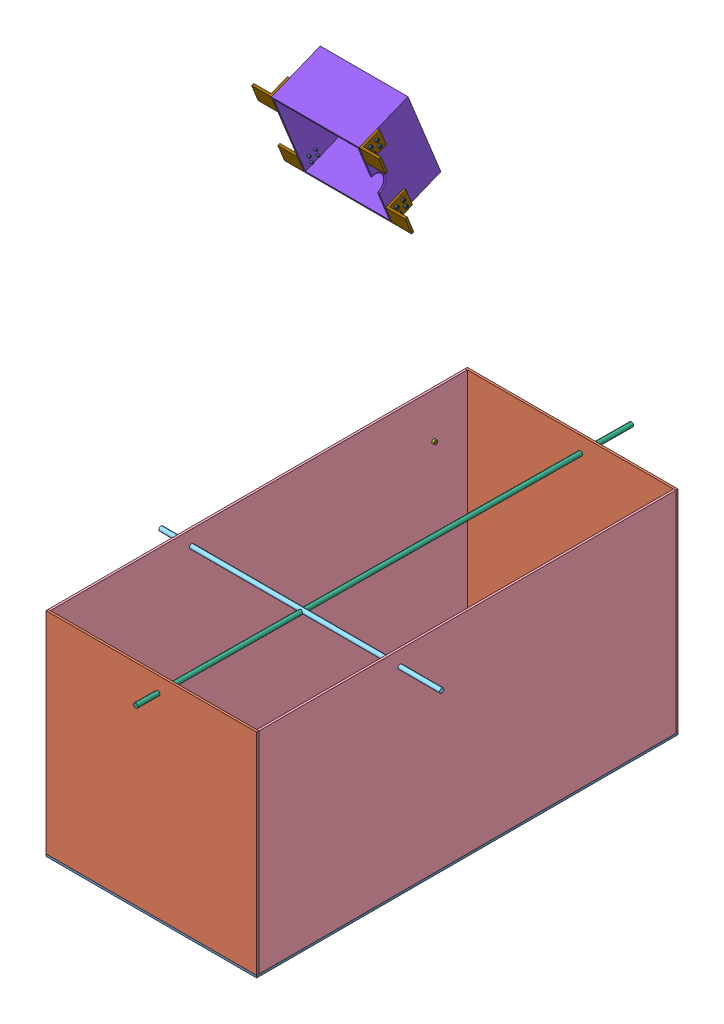
SolidWorks assembly Full Assem 10-31-19, configuration Default. Lengths in mm.
Overall size (741.82 468.9 824.09).
30 component instances, 10 part files, 50 mates.
Components (placement in the parent):
- Base of basin-1: Base of basin [Default] at (176.4368 339.4284 479.3371) size (304.8 3.17 609.6)
- Ends of basin-1: Ends of basin [Default] at (176.4368 495.0034 780.9621) x (0 0 1) z (-1 0 0) size (3.17 304.8 304.8)
- Metalsheet-1: Metalsheet [Default] at (176.9569 345.7784 489.4107) size (254 3.17 254)
- Right Side of basin-1: Right Side of basin [Default] at (24.0368 495.0034 476.1621) size (3.17 304.8 603.25)
- Ends of basin-3: Ends of basin [Default] at (176.4368 495.0034 174.5371) x (0 0 1) z (-1 0 0) size (3.17 304.8 304.8)
- Right Side of basin-2: Right Side of basin [Default] at (325.6618 495.0034 476.1621) size (3.17 304.8 603.25)
- Metal rod 1ft-1: Metal rod 1ft [Default] at (-17.2943 625.8145 576.4898) size (406.4 6.35 6.35)
- Metal rod 2ft-1: Metal rod 2ft [Default] at (191.5519 624.8435 104.5487) x (-0.008727 0 0.999962) z (-0.999962 0 -0.008727) size (711.2 6.35 6.35)
- Standard Servo S3003-1: Standard Servo S3003 [Default] at (12.8608 571.9051 226.3122) x (0 -0.999962 -0.008727) z (1 0 0) size (55.2 19.69 44.46)
- Gear Box-1: Gear Box [Default] at (-260.6438 720.9097 86.1005) x (0 0.927178 0.374622) z (0 0.374622 -0.927178) size (127 127 76.2)
- Gear box Braket-2: Gear box Braket [Default] at (-197.1438 679.1614 53.8226) x (0 -0.927178 -0.374622) z (1 0 0) size (25.4 28.57 28.57)
- Gear box Braket-3: Gear box Braket [Default] at (-324.1438 679.1614 53.8226) x (0 0.927178 0.374622) z (-1 0 0) size (25.4 28.57 28.57)
- Gear box Braket-4: Gear box Braket [Default] at (-197.1438 773.3627 91.8842) x (0 -0.927178 -0.374622) z (1 0 0) size (25.4 28.57 28.57)
- Gear box Braket-5: Gear box Braket [Default] at (-324.1438 773.3627 91.8842) x (0 0.927178 0.374622) z (-1 0 0) size (25.4 28.57 28.57)
- socket head cap screw_ai-2: socket head cap screw_ai [HX-SHCS 0.112-40x0.375x0.375-N] at (-330.1636 776.5265 97.6142) size (12.37 4.65 4.65)
- socket head cap screw_ai-3: socket head cap screw_ai [HX-SHCS 0.112-40x0.375x0.375-N] at (-330.1636 767.1064 93.808) size (12.37 4.65 4.65)
- socket head cap screw_ai-4: socket head cap screw_ai [HX-SHCS 0.112-40x0.375x0.375-N] at (-330.1636 770.9125 84.3879) size (12.37 4.65 4.65)
- socket head cap screw_ai-5: socket head cap screw_ai [HX-SHCS 0.112-40x0.375x0.375-N] at (-330.1636 780.3327 88.1941) size (12.37 4.65 4.65)
- socket head cap screw_ai-6: socket head cap screw_ai [HX-SHCS 0.112-40x0.375x0.375-N] at (-330.1636 676.7113 46.3263) size (12.37 4.65 4.65)
- socket head cap screw_ai-7: socket head cap screw_ai [HX-SHCS 0.112-40x0.375x0.375-N] at (-330.1636 686.1314 50.1325) size (12.37 4.65 4.65)
- socket head cap screw_ai-8: socket head cap screw_ai [HX-SHCS 0.112-40x0.375x0.375-N] at (-330.1636 682.3252 59.5526) size (12.37 4.65 4.65)
- socket head cap screw_ai-9: socket head cap screw_ai [HX-SHCS 0.112-40x0.375x0.375-N] at (-330.1636 672.9051 55.7465) size (12.37 4.65 4.65)
- socket head cap screw_ai-10: socket head cap screw_ai [HX-SHCS 0.112-40x0.375x0.375-N] at (-191.124 780.3327 88.1941) x (-1 0 0) z (0 0.924225 0.381849) size (12.37 4.65 4.65)
- socket head cap screw_ai-11: socket head cap screw_ai [HX-SHCS 0.112-40x0.375x0.375-N] at (-191.124 770.9125 84.3879) x (-1 0 0) z (0 0.924225 0.381849) size (12.37 4.65 4.65)
- socket head cap screw_ai-12: socket head cap screw_ai [HX-SHCS 0.112-40x0.375x0.375-N] at (-191.124 776.5265 97.6142) x (-1 0 0) z (0 0.924225 0.381849) size (12.37 4.65 4.65)
- socket head cap screw_ai-13: socket head cap screw_ai [HX-SHCS 0.112-40x0.375x0.375-N] at (-191.124 767.1064 93.808) x (-1 0 0) z (0 0.924225 0.381849) size (12.37 4.65 4.65)
- socket head cap screw_ai-14: socket head cap screw_ai [HX-SHCS 0.112-40x0.375x0.375-N] at (-191.124 682.3252 59.5526) x (-1 0 0) z (0 0.924225 0.381849) size (12.37 4.65 4.65)
- socket head cap screw_ai-15: socket head cap screw_ai [HX-SHCS 0.112-40x0.375x0.375-N] at (-191.124 686.1314 50.1325) x (-1 0 0) z (0 0.924225 0.381849) size (12.37 4.65 4.65)
- socket head cap screw_ai-16: socket head cap screw_ai [HX-SHCS 0.112-40x0.375x0.375-N] at (-191.124 676.7113 46.3263) x (-1 0 0) z (0 0.924225 0.381849) size (12.37 4.65 4.65)
- socket head cap screw_ai-17: socket head cap screw_ai [HX-SHCS 0.112-40x0.375x0.375-N] at (-191.124 672.9051 55.7465) x (-1 0 0) z (0 0.924225 0.381849) size (12.37 4.65 4.65)
Mates (geometry in assembly coordinates):
- Coincident2: coincident aligned: line of Base of basin-1 through (24.0368 342.6034 784.1371) axis (1 0 0); line of Ends of basin-1 through (24.0368 342.6034 784.1371) axis (1 0 0)
- Coincident3: coincident anti-aligned: line of Base of basin-1 through (24.0368 342.6034 174.5371) axis (0 0 1); line of Ends of basin-1 through (24.0368 342.6034 784.1371) axis (0 0 -1)
- Coincident4: coincident aligned: line of Base of basin-1 through (24.0368 342.6034 174.5371) axis (0 0 1); line of Right Side of basin-1 through (24.0368 342.6034 177.7121) axis (0 0 1)
- Coincident5: coincident anti-aligned: line of Ends of basin-1 through (24.0368 647.4034 780.9621) axis (0 -1 0); line of Right Side of basin-1 through (24.0368 342.6034 780.9621) axis (0 1 0)
- Coincident8: coincident aligned: line of Ends of basin-1 through (328.8368 342.6034 780.9621) axis (0 1 0); line of Right Side of basin-2 through (328.8368 342.6034 780.9621) axis (0 1 0)
- Coincident9: coincident anti-aligned: line of Base of basin-1 through (328.8368 342.6034 784.1371) axis (0 0 -1); line of Right Side of basin-2 through (328.8368 342.6034 177.7121) axis (0 0 1)
- Coincident12: coincident anti-aligned: line of Right Side of basin-1 through (24.0368 342.6034 177.7121) axis (0 1 0); line of Ends of basin-3 through (24.0368 647.4034 177.7121) axis (0 -1 0)
- Coincident13: coincident anti-aligned: line of Base of basin-1 through (24.0368 342.6034 174.5371) axis (0 0 1); line of Ends of basin-3 through (24.0368 342.6034 177.7121) axis (0 0 -1)
- Coincident14: coincident anti-aligned: plane of Base of basin-1 through (176.4368 342.6034 479.3371) normal (0 1 0); plane of Metalsheet-1 through (176.9569 342.6034 489.4107) normal (0 -1 0)
- Coincident16: coincident anti-aligned: plane of Right Side of basin-1 through (24.0368 495.0034 476.1621) normal (-1 0 0); plane of Standard Servo S3003-1 through (24.0368 571.9051 226.3122) normal (1 0 0)
- Coincident25: coincident aligned: line of Gear Box-1 through (-197.1438 706.7795 80.3912) axis (0 -0.927178 -0.374622); line of Gear box Braket-2 through (-197.1438 685.5842 71.8274) axis (0 -0.927178 -0.374622)
- Coincident26: coincident anti-aligned: line of Gear Box-1 through (-197.1438 690.5801 -8.339) axis (0 -0.374622 0.927178); line of Gear box Braket-2 through (-197.1438 662.0339 62.312) axis (0 0.374622 -0.927178)
- Coincident28: coincident aligned: line of Gear Box-1 through (-197.1438 779.7854 109.8889) axis (0 -0.927178 -0.374622); line of Gear box Braket-4 through (-197.1438 779.7854 109.8889) axis (0 -0.927178 -0.374622)
- Coincident30: coincident aligned: line of Gear Box-1 through (-324.1438 662.0339 62.312) axis (0 0.927178 0.374622); line of Gear box Braket-3 through (-324.1438 662.0339 62.312) axis (0 0.927178 0.374622)
- Coincident32: coincident aligned: line of Gear Box-1 through (-197.1438 808.3316 39.238) axis (0 -0.374622 0.927178); line of Gear box Braket-4 through (-197.1438 790.4903 83.3948) axis (0 -0.374622 0.927178)
- Coincident33: coincident aligned: line of Gear Box-1 through (-324.1438 690.5801 -8.339) axis (0 -0.374622 0.927178); line of Gear box Braket-3 through (-324.1438 672.7387 35.8179) axis (0 -0.374622 0.927178)
- Coincident34: coincident aligned: line of Gear Box-1 through (-324.1438 662.0339 62.312) axis (0 0.927178 0.374622); line of Gear box Braket-5 through (-324.1438 756.2351 100.3735) axis (0 0.927178 0.374622)
- Coincident35: coincident anti-aligned: line of Gear Box-1 through (-324.1438 808.3316 39.238) axis (0 -0.374622 0.927178); line of Gear box Braket-5 through (-324.1438 779.7854 109.8889) axis (0 0.374622 -0.927178)
- Concentric3: concentric anti-aligned: cylinder of Gear box Braket-5 through (-352.7188 776.5265 97.6142) axis (1 0 0) radius 1.4097; cylinder of socket head cap screw_ai-2 through (-361.9136 776.5265 97.6142) axis (-1 0 0) radius 2.3241
- Coincident36: coincident anti-aligned: plane of Gear box Braket-5 through (-327.3188 773.3627 91.8842) normal (-1 0 0); plane of socket head cap screw_ai-2 through (-327.3188 778.8506 97.6142) normal (1 0 0)
- Concentric4: concentric anti-aligned: cylinder of Gear box Braket-5 through (-352.7188 767.1064 93.808) axis (1 0 0) radius 1.4097; cylinder of socket head cap screw_ai-3 through (-361.9136 767.1064 93.808) axis (-1 0 0) radius 2.3241
- Coincident37: coincident anti-aligned: plane of Gear box Braket-5 through (-327.3188 773.3627 91.8842) normal (-1 0 0); plane of socket head cap screw_ai-3 through (-327.3188 769.4305 93.808) normal (1 0 0)
- Concentric5: concentric anti-aligned: cylinder of Gear box Braket-5 through (-352.7188 770.9125 84.3879) axis (1 0 0) radius 1.4097; cylinder of socket head cap screw_ai-4 through (-361.9136 770.9125 84.3879) axis (-1 0 0) radius 2.3241
- Coincident38: coincident anti-aligned: plane of Gear box Braket-5 through (-327.3188 773.3627 91.8842) normal (-1 0 0); plane of socket head cap screw_ai-4 through (-327.3188 773.2366 84.3879) normal (1 0 0)
- Concentric6: concentric anti-aligned: cylinder of Gear box Braket-5 through (-352.7188 780.3327 88.1941) axis (1 0 0) radius 1.4097; cylinder of socket head cap screw_ai-5 through (-361.9136 780.3327 88.1941) axis (-1 0 0) radius 2.3241
- Coincident39: coincident anti-aligned: plane of Gear box Braket-5 through (-327.3188 773.3627 91.8842) normal (-1 0 0); plane of socket head cap screw_ai-5 through (-327.3188 782.6568 88.1941) normal (1 0 0)
- Concentric7: concentric anti-aligned: cylinder of Gear box Braket-3 through (-352.7188 676.7113 46.3263) axis (1 0 0) radius 1.4097; cylinder of socket head cap screw_ai-6 through (-361.9136 676.7113 46.3263) axis (-1 0 0) radius 2.3241
- Coincident40: coincident anti-aligned: plane of Gear box Braket-3 through (-327.3188 679.1614 53.8226) normal (-1 0 0); plane of socket head cap screw_ai-6 through (-327.3188 679.0354 46.3263) normal (1 0 0)
- Concentric8: concentric anti-aligned: cylinder of Gear box Braket-3 through (-352.7188 686.1314 50.1325) axis (1 0 0) radius 1.4097; cylinder of socket head cap screw_ai-7 through (-361.9136 686.1314 50.1325) axis (-1 0 0) radius 2.3241
- Coincident41: coincident anti-aligned: plane of Gear box Braket-3 through (-327.3188 679.1614 53.8226) normal (-1 0 0); plane of socket head cap screw_ai-7 through (-327.3188 688.4555 50.1325) normal (1 0 0)
- Concentric9: concentric anti-aligned: cylinder of Gear box Braket-3 through (-352.7188 682.3252 59.5526) axis (1 0 0) radius 1.4097; cylinder of socket head cap screw_ai-8 through (-361.9136 682.3252 59.5526) axis (-1 0 0) radius 2.3241
- Coincident42: coincident anti-aligned: plane of Gear box Braket-3 through (-327.3188 679.1614 53.8226) normal (-1 0 0); plane of socket head cap screw_ai-8 through (-327.3188 684.6493 59.5526) normal (1 0 0)
- Concentric10: concentric anti-aligned: cylinder of Gear box Braket-3 through (-352.7188 672.9051 55.7465) axis (1 0 0) radius 1.4097; cylinder of socket head cap screw_ai-9 through (-361.9136 672.9051 55.7465) axis (-1 0 0) radius 2.3241
- Coincident43: coincident anti-aligned: plane of Gear box Braket-3 through (-327.3188 679.1614 53.8226) normal (-1 0 0); plane of socket head cap screw_ai-9 through (-327.3188 675.2292 55.7465) normal (1 0 0)
- Concentric11: concentric anti-aligned: cylinder of Gear box Braket-4 through (-168.5688 780.3327 88.1941) axis (-1 0 0) radius 1.4097; cylinder of socket head cap screw_ai-10 through (-159.374 780.3327 88.1941) axis (1 0 0) radius 2.3241
- Coincident44: coincident anti-aligned: plane of Gear box Braket-4 through (-193.9688 773.3627 91.8842) normal (1 0 0); plane of socket head cap screw_ai-10 through (-193.9688 779.4452 90.3421) normal (-1 0 0)
- Concentric12: concentric anti-aligned: cylinder of Gear box Braket-4 through (-168.5688 770.9125 84.3879) axis (-1 0 0) radius 1.4097; cylinder of socket head cap screw_ai-11 through (-159.374 770.9125 84.3879) axis (1 0 0) radius 2.3241
- Coincident45: coincident anti-aligned: plane of Gear box Braket-4 through (-193.9688 773.3627 91.8842) normal (1 0 0); plane of socket head cap screw_ai-11 through (-193.9688 770.0251 86.5359) normal (-1 0 0)
- Concentric13: concentric anti-aligned: cylinder of Gear box Braket-4 through (-168.5688 776.5265 97.6142) axis (-1 0 0) radius 1.4097; cylinder of socket head cap screw_ai-12 through (-159.374 776.5265 97.6142) axis (1 0 0) radius 2.3241
- Coincident46: coincident anti-aligned: plane of Gear box Braket-4 through (-193.9688 773.3627 91.8842) normal (1 0 0); plane of socket head cap screw_ai-12 through (-193.9688 775.639 99.7622) normal (-1 0 0)
- Concentric14: concentric anti-aligned: cylinder of Gear box Braket-4 through (-168.5688 767.1064 93.808) axis (-1 0 0) radius 1.4097; cylinder of socket head cap screw_ai-13 through (-159.374 767.1064 93.808) axis (1 0 0) radius 2.3241
- Coincident47: coincident anti-aligned: plane of Gear box Braket-4 through (-193.9688 773.3627 91.8842) normal (1 0 0); plane of socket head cap screw_ai-13 through (-193.9688 766.2189 95.956) normal (-1 0 0)
- Concentric15: concentric anti-aligned: cylinder of Gear box Braket-2 through (-168.5688 682.3252 59.5526) axis (-1 0 0) radius 1.4097; cylinder of socket head cap screw_ai-14 through (-159.374 682.3252 59.5526) axis (1 0 0) radius 2.3241
- Coincident48: coincident anti-aligned: plane of Gear box Braket-2 through (-193.9688 679.1614 53.8226) normal (1 0 0); plane of socket head cap screw_ai-14 through (-193.9688 681.4378 61.7006) normal (-1 0 0)
- Concentric16: concentric anti-aligned: cylinder of Gear box Braket-2 through (-168.5688 686.1314 50.1325) axis (-1 0 0) radius 1.4097; cylinder of socket head cap screw_ai-15 through (-159.374 686.1314 50.1325) axis (1 0 0) radius 2.3241
- Coincident49: coincident anti-aligned: plane of Gear box Braket-2 through (-193.9688 679.1614 53.8226) normal (1 0 0); plane of socket head cap screw_ai-15 through (-193.9688 685.2439 52.2805) normal (-1 0 0)
- Concentric17: concentric anti-aligned: cylinder of Gear box Braket-2 through (-168.5688 676.7113 46.3263) axis (-1 0 0) radius 1.4097; cylinder of socket head cap screw_ai-16 through (-159.374 676.7113 46.3263) axis (1 0 0) radius 2.3241
- Coincident50: coincident anti-aligned: plane of Gear box Braket-2 through (-193.9688 679.1614 53.8226) normal (1 0 0); plane of socket head cap screw_ai-16 through (-193.9688 675.8238 48.4743) normal (-1 0 0)
- Concentric18: concentric anti-aligned: cylinder of Gear box Braket-2 through (-168.5688 672.9051 55.7465) axis (-1 0 0) radius 1.4097; cylinder of socket head cap screw_ai-17 through (-159.374 672.9051 55.7465) axis (1 0 0) radius 2.3241
- Coincident51: coincident anti-aligned: plane of Gear box Braket-2 through (-193.9688 679.1614 53.8226) normal (1 0 0); plane of socket head cap screw_ai-17 through (-193.9688 672.0177 57.8944) normal (-1 0 0)
